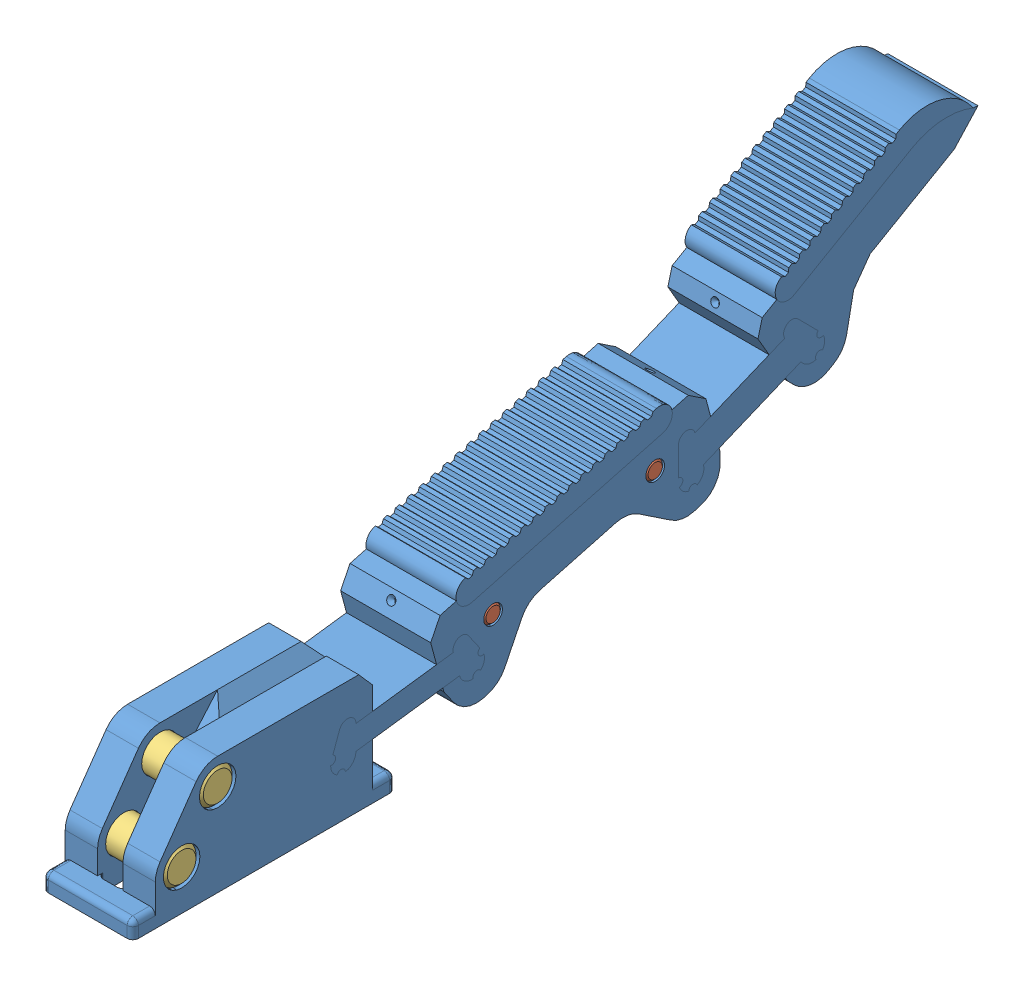
SolidWorks assembly block_finger_ff_t, configuration Default. Lengths in mm.
Overall size (16 58.08 150.14).
7 component instances, 5 part files, 12 mates.
Components (placement in the parent):
- t_ff-1: t_ff [Default] at origin size (16 58.08 150.14)
- 98381A472 D1-8 L5-8-1: 98381A472 D1-8 L5-8 [98381A472] at (0.0625 5.5634 -30.2193) size (15.88 3.17 3.17)
- 98381A472 D1-8 L5-8-2: 98381A472 D1-8 L5-8 [98381A472] at (0.0625 13.2775 -59.0086) size (15.88 3.17 3.17)
- 98381A539 D1-4 L5-8-1: 98381A539 D1-4 L5-8 [98381A539] at (0.0625 3.5418 18.7031) size (15.88 6.35 6.35)
- 98381A539 D1-4 L5-8-2: 98381A539 D1-4 L5-8 [98381A539] at (0.0625 -5.6082 25.11) size (15.88 6.35 6.35)
- 93365A120 4-40 insert-1: 93365A120 4-40 insert [93365A120] at (0 25.5032 -95.7226) x (1 0 0) z (0 0.812659 -0.582739) size (4.37 3.82 4.37)
- 91253A106 4-40 L1-4 countersunk-1: 91253A106 4-40 L1-4 countersunk [91253A106] at (0 24.2671 -97.4464) x (0.996599 0.066964 -0.048019) z (0 -0.582739 -0.812659) size (6.48 6.48 6.63)
Mates (geometry in assembly coordinates):
- Concentric1: concentric: cylinder of t_ff-1 through (-8 13.2775 -59.0086) axis (1 0 0) radius 1.6625; cylinder of 98381A472 D1-8 L5-8-2 through (-7.875 13.2775 -59.0086) axis (1 0 0) radius 1.5875
- Coincident1: coincident: plane of t_ff-1 through (8 0 0) normal (1 0 0); plane of 98381A472 D1-8 L5-8-2 through (8 13.2775 -59.0086) normal (1 0 0)
- Concentric2: concentric: cylinder of t_ff-1 through (-8 5.5634 -30.2193) axis (1 0 0) radius 1.6625; cylinder of 98381A472 D1-8 L5-8-1 through (-7.875 5.5634 -30.2193) axis (1 0 0) radius 1.5875
- Coincident2: coincident: plane of t_ff-1 through (8 0 0) normal (1 0 0); plane of 98381A472 D1-8 L5-8-1 through (8 5.5634 -30.2193) normal (1 0 0)
- Concentric3: concentric: cylinder of t_ff-1 through (-8 3.5418 18.7031) axis (1 0 0) radius 3.25; cylinder of 98381A539 D1-4 L5-8-1 through (-7.875 3.5418 18.7031) axis (1 0 0) radius 3.175
- Coincident3: coincident: plane of t_ff-1 through (8 0 0) normal (1 0 0); plane of 98381A539 D1-4 L5-8-1 through (8 3.5418 18.7031) normal (1 0 0)
- Concentric4: concentric: cylinder of t_ff-1 through (-8 -5.6082 25.11) axis (1 0 0) radius 3.25; cylinder of 98381A539 D1-4 L5-8-2 through (-7.875 -5.6082 25.11) axis (1 0 0) radius 3.175
- Coincident4: coincident: plane of t_ff-1 through (8 0 0) normal (1 0 0); plane of 98381A539 D1-4 L5-8-2 through (8 -5.6082 25.11) normal (1 0 0)
- Concentric5: concentric: cylinder of t_ff-1 through (0 28.1256 -92.0656) axis (0 -0.582739 -0.812659) radius 1.85; circle of 93365A120 4-40 insert-1
- Coincident5: coincident: plane of t_ff-1 through (-13 27.5349 -97.1794) normal (0 -0.582739 -0.812659); plane of 93365A120 4-40 insert-1 through (0 25.5032 -95.7226) normal (0 -0.582739 -0.812659)
- Concentric6: concentric: circle of 93365A120 4-40 insert-1; circle of 91253A106 4-40 L1-4 countersunk-1
- Coincident6: coincident: circle of 93365A120 4-40 insert-1; cone of 91253A106 4-40 L1-4 countersunk-1 through (0 25.4957 -95.7331) axis (0 0.582739 0.812659)
